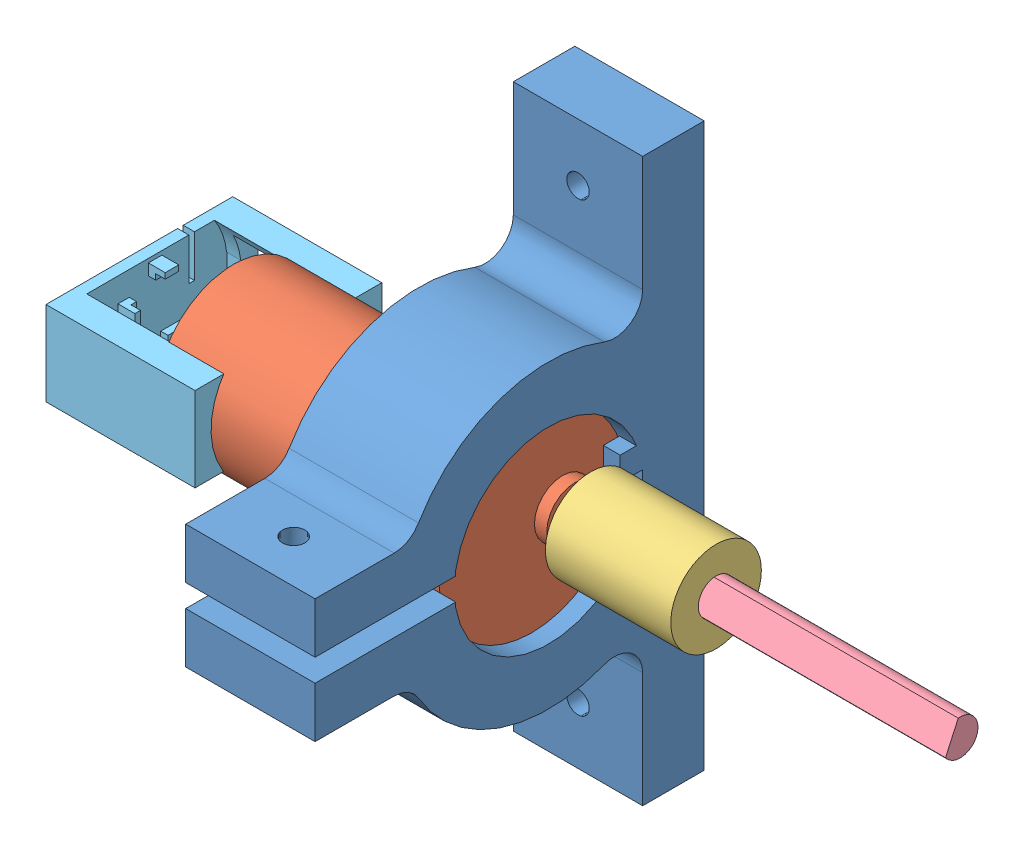
SolidWorks assembly NEW_wheel_assem, configuration Default. Lengths in mm.
Overall size (140.44 100 69.19).
5 component instances, 5 part files, 12 mates.
Components (placement in the parent):
- Motor Mount.ipt-1: Motor Mount.ipt [Default] at origin size (23 100 69.19)
- Motor v3.ipt-1: Motor v3.ipt [Default] at (20 0 0) x (1 0 0) z (0 0 -1) size (65.4 33 33)
- coupler-1: coupler [Default] at (89.15 0 -5.5) x (0 0.976084 0.217394) z (0 0.217394 -0.976084) size (16.1 22.3 16.1)
- drive_shaft-1: drive_shaft [Default] at (143.7 0 -5.5) x (0 -0.910539 0.413423) z (0 -0.413423 -0.910539) size (6.35 50.8 4.79)
- Encoder_BracketMount-1: Encoder_BracketMount [Default] at (5.2593 0 0) x (0 1 0) z (1 0 0) size (15 33.2 26.5)
Mates (geometry in assembly coordinates):
- Coincident1: coincident aligned: plane of Motor Mount.ipt-1 through (0 0 0) normal (0 0 1)
- Coincident2: coincident aligned: plane of Motor Mount.ipt-1 through (0 0 0) normal (0 1 0)
- Coincident3: coincident aligned: plane of Motor Mount.ipt-1 through (0 0 0) normal (1 0 0)
- Concentric1: concentric aligned: cylinder of Motor Mount.ipt-1 through (53 0 0) axis (-1 0 0) radius 16.75; cylinder of Motor v3.ipt-1 through (53 0 0) axis (-1 0 0) radius 16.5
- Coincident4: coincident anti-aligned: plane of Motor Mount.ipt-1 through (73 3.875 -14.7042) normal (-1 0 0); plane of Motor v3.ipt-1 through (73 0 0) normal (1 0 0)
- Parallel1: parallel anti-aligned: plane of Motor Mount.ipt-1 through (53 11 41.5) normal (0 0 1); plane of Motor v3.ipt-1 through (75.2 -1.9209 -7.1) normal (0 0 -1)
- Concentric2: concentric aligned: cylinder of Motor v3.ipt-1 through (75.2 0 -5.5) axis (-1 0 0) radius 2.5; cylinder of coupler-1 through (85.4 0 -5.5) axis (-1 0 0) radius 2.54
- Coincident6: coincident anti-aligned: plane of Motor v3.ipt-1 through (85.4 0 -5.05) normal (1 0 0); plane of coupler-1 through (85.4 0 -5.5) normal (-1 0 0)
- Coincident7: coincident aligned: circle of coupler-1; cylinder of drive_shaft-1 through (92.9 0 -5.5) axis (1 0 0) radius 3.175
- Coincident8: coincident anti-aligned: plane of coupler-1 through (92.9 0 -5.5) normal (1 0 0); plane of drive_shaft-1 through (92.9 0 -5.5) normal (-1 0 0)
- Concentric3: concentric aligned: cylinder of Motor v3.ipt-1 through (20 0 0) axis (-1 0 0) radius 13.75; cylinder of Encoder_BracketMount-1 through (19.7593 0 0) axis (-1 0 0) radius 13.6
- Parallel2: parallel aligned: plane of Motor Mount.ipt-1 through (53 -50 -27.6898) normal (0 0 -1); plane of Encoder_BracketMount-1 through (3.2593 0 -16.6) normal (0 0 -1)
